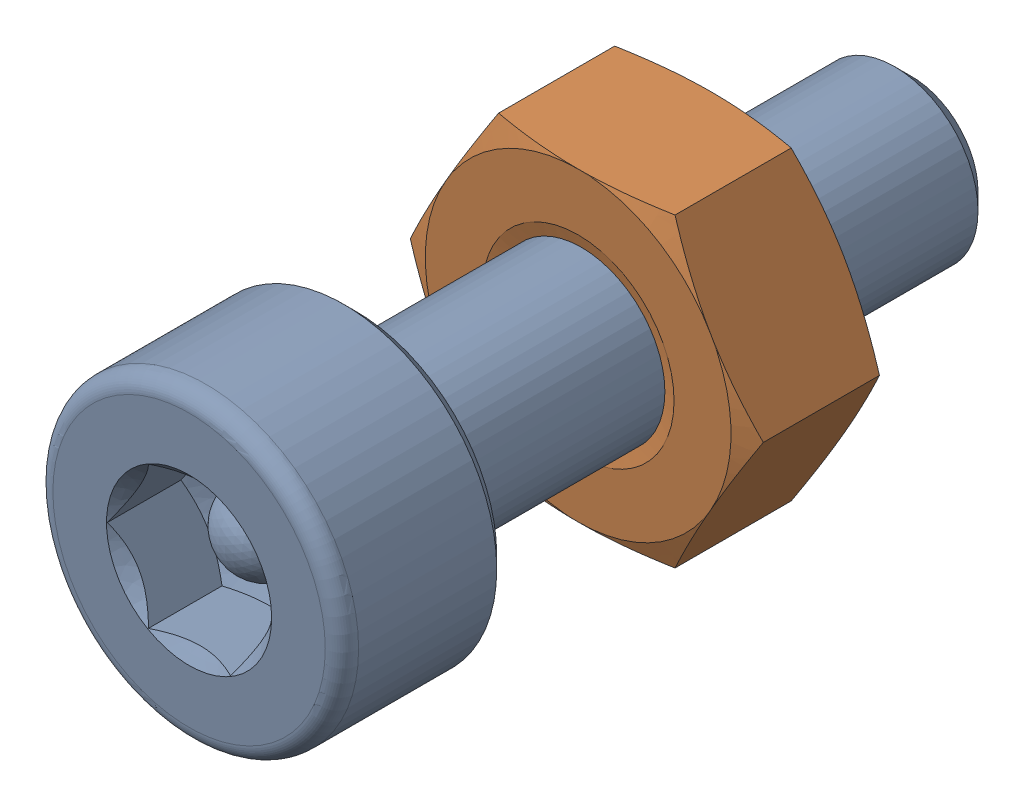
SolidWorks assembly Screw and Nut M3x010_016, configuration Varsayılan. Lengths in mm.
Overall size (6.35 5.5 13.14).
2 component instances, 2 part files, 0 mates.
Components (placement in the parent):
- M3x10-Screw015-1: M3x10-Screw015 [Varsayılan] at origin size (5.5 5.5 13.14)
- M3-Nut047-1: M3-Nut047 [Varsayılan] at (0 0 -4) x (-1 0 0) z (0 0 -1) size (6.35 5.5 2.4)
